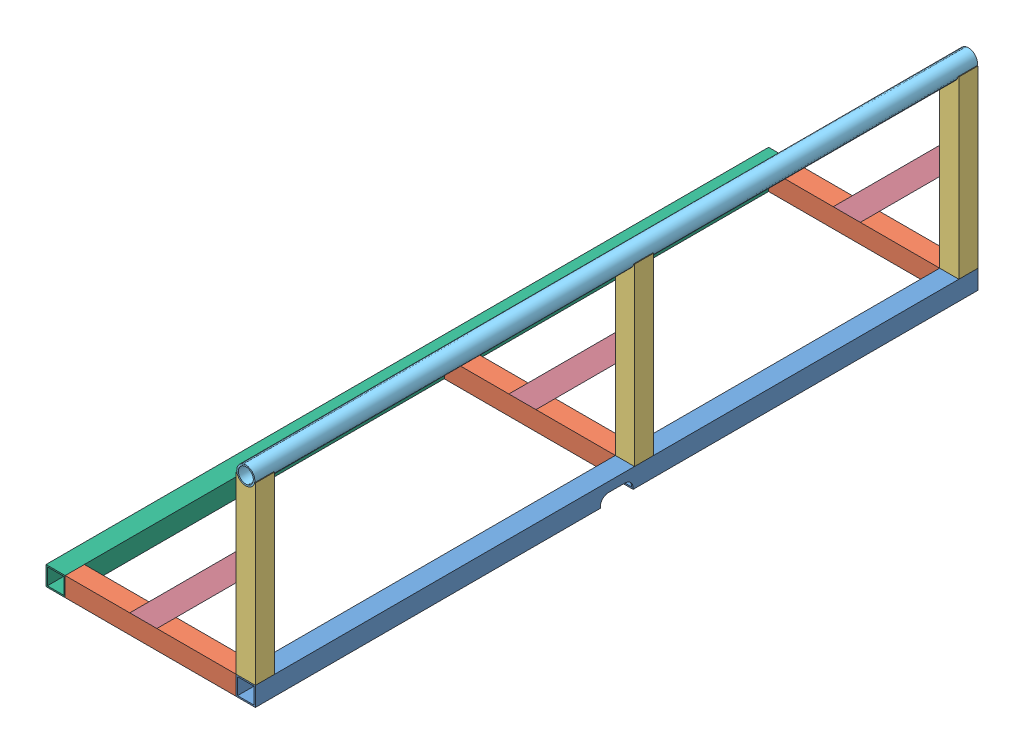
SolidWorks assembly GE-18051, configuration Default. Lengths in mm.
Overall size (485.78 476.25 1676.4).
12 component instances, 6 part files, 35 mates.
Components (placement in the parent):
- GE-18051-01-1: GE-18051-01 [Default] x (1 0 0) z (0 1 0) size (44.45 1676.4 44.45)
- GE-18051-02-1: GE-18051-02 [Default] at (0 838.2 793.75) size (396.88 44.45 44.45)
- GE-18051-03-1: GE-18051-03 [Default] x (1 0 0) z (0 1 0) size (44.45 44.45 406.4)
- GE-18051-04-1: GE-18051-04 [Default] x (1 0 0) z (0 1 0) size (246.96 44.45 246.96)
- GE-18051-05-1: GE-18051-05 [Default] at (0 910.336 0) x (1 0 0) z (0 -1 0) size (42.16 1676.4 42.16)
- GE-18051-02-2: GE-18051-02 [Default] at (0 838.2 -85.725) size (396.88 44.45 44.45)
- GE-18051-02-3: GE-18051-02 [Default] at (0 838.2 -838.2) size (396.88 44.45 44.45)
- GE-18051-03-2: GE-18051-03 [Default] at (0 0 -879.475) x (1 0 0) z (0 1 0) size (44.45 44.45 406.4)
- GE-18051-03-3: GE-18051-03 [Default] at (0 0 -1631.95) x (1 0 0) z (0 1 0) size (44.45 44.45 406.4)
- GE-18051-04-2: GE-18051-04 [Default] at (0 0 -1631.95) x (1 0 0) z (0 1 0) size (246.96 44.45 246.96)
- GE-18051-04-3: GE-18051-04 [Default] at (0 0 -879.475) x (1 0 0) z (0 1 0) size (246.96 44.45 246.96)
- GE-18051-06-1: GE-18051-06 [Default] at (15.875 0 0) x (1 0 0) z (0 1 0) size (44.45 1676.4 44.45)
Mates (geometry in assembly coordinates):
- Coincident1: coincident aligned: plane of GE-18051-01-1 through (0 0 0) normal (0 1 0); plane of assembly through (0 0 0) normal (0 1 0)
- Coincident3: coincident aligned: plane of ? through (0 0 0) normal (1 0 0)
- Coincident4: coincident anti-aligned: plane of ? through (0 0 0) normal (0 0 -1)
- Coincident5: coincident anti-aligned: plane of GE-18051-01-1 through (352.425 44.45 0) normal (0 1 0); plane of GE-18051-03-1 through (682.625 44.45 0) normal (0 -1 0)
- Coincident6: coincident aligned: plane of GE-18051-01-1 through (682.625 44.45 838.2) normal (0 0 1); plane of GE-18051-03-1 through (682.625 450.85 838.2) normal (0 0 1)
- Coincident7: coincident aligned: plane of GE-18051-01-1 through (704.85 44.45 0) normal (1 0 0); plane of GE-18051-03-1 through (704.85 450.85 0) normal (1 0 0)
- Coincident8: coincident anti-aligned: plane of GE-18051-01-1 through (352.425 44.45 0) normal (0 1 0); plane of GE-18051-03-3 through (682.625 44.45 -1631.95) normal (0 -1 0)
- Coincident9: coincident aligned: plane of GE-18051-01-1 through (704.85 44.45 0) normal (1 0 0); plane of GE-18051-03-3 through (704.85 450.85 -1631.95) normal (1 0 0)
- Coincident10: coincident aligned: plane of GE-18051-01-1 through (682.625 44.45 -838.2) normal (0 0 -1); plane of GE-18051-03-3 through (663.575 450.85 -838.2) normal (0 0 -1)
- Coincident11: coincident anti-aligned: plane of GE-18051-01-1 through (352.425 44.45 0) normal (0 1 0); plane of GE-18051-03-2 through (682.625 44.45 -879.475) normal (0 -1 0)
- Distance1: distance = 879.475 mm aligned: plane of GE-18051-03-2 through (663.575 450.85 -85.725) normal (0 0 -1); plane of GE-18051-03-1 through (663.575 450.85 793.75) normal (0 0 -1)
- Coincident13: coincident anti-aligned: plane of GE-18051-01-1 through (660.4 44.45 0) normal (-1 0 0); plane of GE-18051-02-1 through (660.4 22.225 838.2) normal (1 0 0)
- Coincident14: coincident aligned: plane of GE-18051-01-1 through (682.625 44.45 838.2) normal (0 0 1); plane of GE-18051-02-1 through (461.9625 22.225 838.2) normal (0 0 1)
- Coincident15: coincident aligned: plane of GE-18051-01-1 through (352.425 44.45 0) normal (0 1 0); plane of GE-18051-02-1 through (461.9625 44.45 838.2) normal (0 1 0)
- Coincident16: coincident anti-aligned: plane of GE-18051-01-1 through (660.4 44.45 0) normal (-1 0 0); plane of GE-18051-02-2 through (660.4 22.225 -41.275) normal (1 0 0)
- Coincident17: coincident aligned: plane of GE-18051-02-2 through (461.9625 22.225 -41.275) normal (0 0 1); plane of GE-18051-03-2 through (682.625 450.85 -41.275) normal (0 0 1)
- Coincident18: coincident aligned: plane of GE-18051-01-1 through (352.425 44.45 0) normal (0 1 0); plane of GE-18051-02-2 through (461.9625 44.45 -41.275) normal (0 1 0)
- Coincident19: coincident aligned: plane of GE-18051-01-1 through (704.85 44.45 0) normal (1 0 0); plane of GE-18051-03-2 through (704.85 450.85 -879.475) normal (1 0 0)
- Coincident20: coincident anti-aligned: plane of GE-18051-01-1 through (660.4 44.45 0) normal (-1 0 0); plane of GE-18051-02-3 through (660.4 22.225 -793.75) normal (1 0 0)
- Coincident21: coincident aligned: plane of GE-18051-01-1 through (352.425 44.45 0) normal (0 1 0); plane of GE-18051-02-3 through (461.9625 44.45 -793.75) normal (0 1 0)
- Coincident22: coincident aligned: plane of GE-18051-02-3 through (461.9625 22.225 -793.75) normal (0 0 1); plane of GE-18051-03-3 through (682.625 450.85 -793.75) normal (0 0 1)
- Coincident23: coincident anti-aligned: plane of GE-18051-03-1 through (660.4 450.85 0) normal (-1 0 0); plane of GE-18051-04-1 through (660.4 450.85 793.75) normal (1 0 0)
- Coincident24: coincident anti-aligned: plane of GE-18051-02-1 through (461.9625 44.45 838.2) normal (0 1 0); plane of GE-18051-04-1 through (430.6402 44.45 793.75) normal (0 -1 0)
- Coincident25: coincident aligned: plane of GE-18051-03-1 through (682.625 450.85 838.2) normal (0 0 1); plane of GE-18051-04-1 through (484.1875 247.65 838.2) normal (0 0 1)
- Coincident26: coincident anti-aligned: plane of GE-18051-02-2 through (461.9625 44.45 -41.275) normal (0 1 0); plane of GE-18051-04-3 through (430.6402 44.45 -85.725) normal (0 -1 0)
- Coincident27: coincident anti-aligned: plane of GE-18051-03-2 through (660.4 450.85 -879.475) normal (-1 0 0); plane of GE-18051-04-3 through (660.4 450.85 -85.725) normal (1 0 0)
- Coincident28: coincident aligned: plane of GE-18051-03-2 through (682.625 450.85 -41.275) normal (0 0 1); plane of GE-18051-04-3 through (484.1875 247.65 -41.275) normal (0 0 1)
- Coincident29: coincident anti-aligned: plane of GE-18051-02-3 through (461.9625 44.45 -793.75) normal (0 1 0); plane of GE-18051-04-2 through (430.6402 44.45 -838.2) normal (0 -1 0)
- Coincident30: coincident anti-aligned: plane of GE-18051-03-3 through (660.4 450.85 -1631.95) normal (-1 0 0); plane of GE-18051-04-2 through (660.4 450.85 -838.2) normal (1 0 0)
- Coincident31: coincident aligned: plane of GE-18051-03-3 through (682.625 450.85 -793.75) normal (0 0 1); plane of GE-18051-04-2 through (484.1875 247.65 -793.75) normal (0 0 1)
- Concentric1: concentric: cylinder of GE-18051-03-1 through (682.625 455.168 793.748) axis (0 0 -1) radius 21.082; cylinder of GE-18051-05-1 through (682.625 455.168 838.202) axis (0 0 1) radius 21.082
- Coincident32: coincident aligned: plane of GE-18051-03-1 through (682.625 450.85 838.2) normal (0 0 1); plane of GE-18051-05-1 through (682.625 865.886 838.2) normal (0 0 1)
- Coincident33: coincident: plane of GE-18051-02-1 through (263.525 22.225 838.2) normal (-1 0 0); plane of GE-18051-06-1 through (263.525 44.45 0) normal (1 0 0)
- Coincident34: coincident: plane of GE-18051-02-1 through (461.9625 44.45 838.2) normal (0 1 0); plane of GE-18051-06-1 through (-88.9 44.45 0) normal (0 1 0)
- Coincident35: coincident aligned: plane of GE-18051-02-1 through (461.9625 22.225 838.2) normal (0 0 1); plane of GE-18051-06-1 through (241.3 44.45 838.2) normal (0 0 1)
